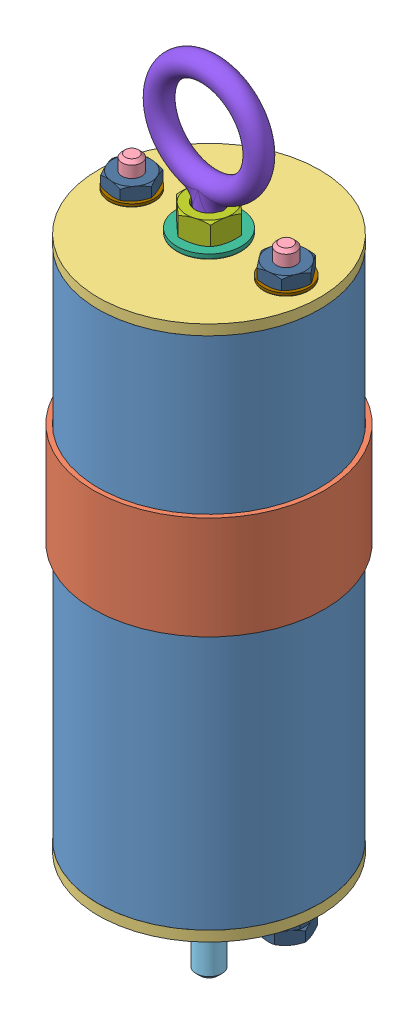
SolidWorks assembly Ebay Assembly, configuration Default. Lengths in mm.
Overall size (56.95 195.52 56.95).
37 component instances, 17 part files, 75 mates.
Components (placement in the parent):
- Coupler-1: Coupler [Default] at origin size (54.61 127 54.61)
- Body Tube-1: Body Tube [Switch Band] at (0 63.5 0) size (56.95 25.4 56.95)
- Bulkhead-1: Bulkhead [Default] at (0 -2.54 0) size (54.61 5.08 54.61)
- Bulkhead-2: Bulkhead [Default] at (0 129.54 0) x (-1 0 0) z (0 0 1) size (54.61 5.08 54.61)
- num10 threaded rod-1: num10 threaded rod [94435A511] at (19.05 63.5 0) x (0 -1 0) z (-0.767639 0 0.640883) size (147.32 4.83 4.83)
- num10 threaded rod-3: num10 threaded rod [94435A511] at (-19.05 63.5 0) x (0 -1 0) z (-0.633107 0 0.774065) size (147.32 4.83 4.83)
- 1-4 20 threaded rod-1: 1-4 20 threaded rod [94435A313] at (0 -8.89 0) x (0 1 0) z (-0.295098 0 0.955467) size (38.1 6.35 6.35)
- 1-4 washer-1: 1-4 washer [90107A029] at (0 -3.175 0) x (1 0 0) z (0 1 0) size (15.88 15.88 1.27)
- 1-4 washer-2: 1-4 washer [90107A029] at (0 3.175 0) x (-0.982082 0 -0.188455) z (0 -1 0) size (15.88 15.88 1.27)
- 1-4 20 nut-1: 1-4 20 nut [90670A029] at (0 6.5881 0) x (1 0 0) z (0 1 0) size (11.11 12.83 5.56)
- 1-4 20 nut-2: 1-4 20 nut [90670A029] at (0 -6.5881 0) x (-0.982082 0 -0.188455) z (0 -1 0) size (11.11 12.83 5.56)
- 1-4 washer-4: 1-4 washer [90107A029] at (0 123.825 0) x (0.982082 0 -0.188455) z (0 1 0) size (15.88 15.88 1.27)
- 1-4 washer-6: 1-4 washer [90107A029] at (0 130.175 0) x (-0.918365 0 -0.395734) z (0 -1 0) size (15.88 15.88 1.27)
- 1-4 20 nut-4: 1-4 20 nut [90670A029] at (0 120.4119 0) x (-1 0 0) z (0 -1 0) size (11.11 12.83 5.56)
- 1-4 20 nut-6: 1-4 20 nut [90670A029] at (0 133.5881 0) x (0.976488 0 0.215573) z (0 1 0) size (11.11 12.83 5.56)
- eyebolt-1: eyebolt [33045T71] at (0 152.499 0) size (30.16 50.16 7.13)
- num10 washer-1: num10 washer [90107A011] at (-19.05 129.9337 0) x (1 0 0) z (0 -1 0) size (11.13 11.13 0.79)
- num10 washer-2: num10 washer [90107A011] at (19.05 129.9337 0) x (0.982082 0 -0.188455) z (0 -1 0) size (11.13 11.13 0.79)
- num10 washer-4: num10 washer [90107A011] at (-19.05 -2.9337 0) x (-0.918365 0 -0.395734) z (0 1 0) size (11.13 11.13 0.79)
- num10 washer-6: num10 washer [90107A011] at (19.05 -2.9337 0) x (-0.8 0 -0.6) z (0 1 0) size (11.13 11.13 0.79)
- num10 nut-1: num10 nut [93181A011] at (-19.05 -4.9149 0) size (9.53 3.17 11)
- num10 nut-2: num10 nut [93181A011] at (19.05 -4.9149 0) x (0.982082 0 -0.188455) z (0.188455 0 0.982082) size (9.53 3.17 11)
- num10 nut-4: num10 nut [93181A011] at (19.05 131.9149 0) x (-0.918365 0 -0.395734) z (-0.395734 0 0.918365) size (9.53 3.17 11)
- num10 nut-6: num10 nut [93181A011] at (-19.05 131.9149 0) x (-0.8 0 -0.6) z (-0.6 0 0.8) size (9.53 3.17 11)
- num10 nut-8: num10 nut [93181A011] at (-19.05 -8.0899 0) x (0.982082 0 -0.188455) z (0.188455 0 0.982082) size (9.53 3.17 11)
- num10 nut-10: num10 nut [93181A011] at (19.05 -8.0899 0) x (0.918365 0 -0.395734) z (0.395734 0 0.918365) size (9.53 3.17 11)
- Ebay Sled-1: Ebay Sled [Default] at origin size (45.72 104.14 22.77)
- Raven 4 v9.step-1: Raven 4 v9.step [Default] at (10.033 113.03 9.3218) x (0 -1 0) z (0 0 -1) size (44.96 20.26 13.9)
- GPS Tracker v15.step-4: GPS Tracker v15.step [Default] at (-6.35 51.562 -9.652) x (0 -1 0) z (0 0 -1) size (103.47 20.32 17.72)
- easymini-1: easymini [Default] at (0 51.47 8.89) x (1 0 0) z (0 -1 0) size (38.1 12.95 20.32)
- 400mAh batt-1: 400mAh batt [Bottom] at (-3.7735 23.83 7.254) x (-1 0 0) z (0 0 -1) size (35.37 24.97 4.58)
- 400mAh batt-2: 400mAh batt [Bottom] at (-3.7735 23.83 11.754) x (-1 0 0) z (0 0 -1) size (35.37 24.97 4.58)
- 400mAh batt-3: 400mAh batt [Bottom] at (0 32.2622 0.874) x (0 1 0) z (0 0 1) size (35.37 24.97 4.58)
- Screw switch-1: Screw switch [Standard] at (-18.8981 72.4535 -9.8604) x (0 1 0) z (0.5 0 -0.866025) size (31.75 1.52 10.16)
- ss screw-1: ss screw [91772A142] at (-19.25 76.2 -10.0636) x (-0.09665 -0.98114 0.167404) z (-0.866025 0 -0.5) size (6.86 6.86 5.58)
- Screw switch-2: Screw switch [Standard] at (18.8981 72.4535 -9.8604) x (0 1 0) z (0.5 0 0.866025) size (31.75 1.52 10.16)
- ss screw-2: ss screw [91772A142] at (19.25 76.2 -10.0636) x (-0.09665 0.98114 -0.167404) z (0.866025 0 -0.5) size (6.86 6.86 5.58)
Mates (geometry in assembly coordinates):
- Concentric1: concentric aligned: cylinder of Coupler-1 through (0 127 0) axis (0 -1 0) radius 25.4; cylinder of Bulkhead-1 through (0 2.54 0) axis (0 -1 0) radius 25.4
- Coincident1: coincident anti-aligned: plane of Coupler-1 through (0 0 0) normal (0 -1 0); plane of Bulkhead-1 through (0 0 0) normal (0 1 0)
- Concentric2: concentric anti-aligned: cylinder of Coupler-1 through (0 127 0) axis (0 -1 0) radius 25.4; cylinder of Bulkhead-2 through (0 124.46 0) axis (0 1 0) radius 25.4
- Coincident2: coincident anti-aligned: plane of Coupler-1 through (0 127 0) normal (0 1 0); plane of Bulkhead-2 through (0 127 0) normal (0 -1 0)
- Concentric3: concentric aligned: cylinder of Coupler-1 through (0 127 0) axis (0 -1 0) radius 27.305; cylinder of Body Tube-1 through (0 88.9 0) axis (0 -1 0) radius 27.3304
- Distance1: distance = 63.5 mm aligned: plane of Coupler-1 through (0 0 0) normal (0 -1 0); plane of Body Tube-1 through (0 63.5 0) normal (0 -1 0)
- Concentric4: concentric anti-aligned: cylinder of Bulkhead-1 through (19.05 2.541 0) axis (0 -1 0) radius 2.413; cylinder of Bulkhead-2 through (19.05 124.459 0) axis (0 1 0) radius 2.413
- Concentric5: concentric anti-aligned: cylinder of Bulkhead-2 through (19.05 124.459 0) axis (0 1 0) radius 2.413; cylinder of num10 threaded rod-1 through (19.05 137.16 0) axis (0 -1 0) radius 2.413
- Width1: width aligned: plane of num10 threaded rod-1 through (19.05 137.16 0) normal (0 1 0); plane of num10 threaded rod-1 through (19.05 -10.16 0) normal (0 -1 0); plane of Bulkhead-2 through (0 129.54 0) normal (0 1 0); plane of Bulkhead-1 through (0 -2.54 0) normal (0 -1 0)
- Concentric6: concentric anti-aligned: cylinder of Bulkhead-2 through (-19.05 124.459 0) axis (0 1 0) radius 2.413; cylinder of num10 threaded rod-3 through (-19.05 137.16 0) axis (0 -1 0) radius 2.413
- Width2: width aligned: plane of num10 threaded rod-3 through (-19.05 137.16 0) normal (0 1 0); plane of num10 threaded rod-3 through (-19.05 -10.16 0) normal (0 -1 0); plane of Bulkhead-1 through (0 -2.54 0) normal (0 -1 0); plane of Bulkhead-2 through (0 129.54 0) normal (0 1 0)
- Concentric7: concentric anti-aligned: cylinder of num10 threaded rod-3 through (-19.05 137.16 0) axis (0 -1 0) radius 2.413; cylinder of num10 washer-1 through (-19.05 129.54 0) axis (0 1 0) radius 2.5781
- Coincident3: coincident anti-aligned: plane of Bulkhead-2 through (0 129.54 0) normal (0 1 0); plane of num10 washer-1 through (-19.05 129.54 0) normal (0 -1 0)
- Concentric8: concentric anti-aligned: cylinder of num10 threaded rod-1 through (19.05 137.16 0) axis (0 -1 0) radius 2.413; cylinder of num10 washer-2 through (19.05 129.54 0) axis (0 1 0) radius 2.5781
- Coincident4: coincident anti-aligned: plane of Bulkhead-2 through (0 129.54 0) normal (0 1 0); plane of num10 washer-2 through (19.05 129.54 0) normal (0 -1 0)
- Concentric9: concentric aligned: cylinder of num10 threaded rod-3 through (-19.05 137.16 0) axis (0 -1 0) radius 2.413; cylinder of num10 washer-4 through (-19.05 -2.54 0) axis (0 -1 0) radius 2.5781
- Coincident5: coincident anti-aligned: plane of Bulkhead-1 through (0 -2.54 0) normal (0 -1 0); plane of num10 washer-4 through (-19.05 -2.54 0) normal (0 1 0)
- Concentric10: concentric aligned: cylinder of num10 threaded rod-1 through (19.05 137.16 0) axis (0 -1 0) radius 2.413; cylinder of num10 washer-6 through (19.05 -2.54 0) axis (0 -1 0) radius 2.5781
- Coincident6: coincident anti-aligned: plane of Bulkhead-1 through (0 -2.54 0) normal (0 -1 0); plane of num10 washer-6 through (19.05 -2.54 0) normal (0 1 0)
- Concentric11: concentric aligned: cylinder of num10 threaded rod-3 through (-19.05 137.16 0) axis (0 -1 0) radius 2.413; cylinder of num10 nut-1 through (-19.05 -3.3274 0) axis (0 -1 0) radius 2.413
- Coincident7: coincident anti-aligned: plane of num10 washer-4 through (-19.05 -3.3274 0) normal (0 -1 0); plane of num10 nut-1 through (-23.8125 -3.3274 -2.7496) normal (0 1 0)
- Concentric12: concentric aligned: cylinder of num10 threaded rod-1 through (19.05 137.16 0) axis (0 -1 0) radius 2.413; cylinder of num10 nut-2 through (19.05 -3.3274 0) axis (0 -1 0) radius 2.413
- Coincident8: coincident anti-aligned: plane of num10 washer-6 through (19.05 -3.3274 0) normal (0 -1 0); plane of num10 nut-2 through (13.8547 -3.3274 -1.8028) normal (0 1 0)
- Concentric13: concentric anti-aligned: cylinder of num10 threaded rod-1 through (19.05 137.16 0) axis (0 -1 0) radius 2.413; cylinder of num10 nut-4 through (19.05 130.3274 0) axis (0 1 0) radius 2.413
- Coincident9: coincident anti-aligned: plane of num10 washer-2 through (19.05 130.3274 0) normal (0 1 0); plane of num10 nut-4 through (24.5118 130.3274 -0.6405) normal (0 -1 0)
- Concentric14: concentric anti-aligned: cylinder of num10 threaded rod-3 through (-19.05 137.16 0) axis (0 -1 0) radius 2.413; cylinder of num10 nut-6 through (-19.05 130.3274 0) axis (0 1 0) radius 2.413
- Coincident10: coincident anti-aligned: plane of num10 washer-1 through (-19.05 130.3274 0) normal (0 1 0); plane of num10 nut-6 through (-13.5902 130.3274 0.6578) normal (0 -1 0)
- Concentric15: concentric aligned: cylinder of num10 threaded rod-3 through (-19.05 137.16 0) axis (0 -1 0) radius 2.413; cylinder of num10 nut-8 through (-19.05 -6.5024 0) axis (0 -1 0) radius 2.413
- Coincident11: coincident anti-aligned: plane of num10 nut-1 through (-23.8125 -6.5024 -2.7496) normal (0 -1 0); plane of num10 nut-8 through (-24.2453 -6.5024 -1.8028) normal (0 1 0)
- Concentric16: concentric aligned: cylinder of num10 threaded rod-1 through (19.05 137.16 0) axis (0 -1 0) radius 2.413; cylinder of num10 nut-10 through (19.05 -6.5024 0) axis (0 -1 0) radius 2.413
- Coincident12: coincident anti-aligned: plane of num10 nut-2 through (13.8547 -6.5024 -1.8028) normal (0 -1 0); plane of num10 nut-10 through (13.5882 -6.5024 -0.6405) normal (0 1 0)
- Distance2: distance = 7.62 mm aligned: plane of 1-4 20 threaded rod-1 through (0 10.16 0) normal (0 1 0); plane of Bulkhead-1 through (0 2.54 0) normal (0 1 0)
- Concentric18: concentric anti-aligned: cylinder of Bulkhead-1 through (0 2.541 0) axis (0 -1 0) radius 3.3346; cylinder of 1-4 20 threaded rod-1 through (0 -27.94 0) axis (0 1 0) radius 3.175
- Concentric19: concentric anti-aligned: cylinder of 1-4 20 threaded rod-1 through (0 -27.94 0) axis (0 1 0) radius 3.175; cylinder of 1-4 washer-1 through (0 -2.54 0) axis (0 -1 0) radius 3.5687
- Coincident13: coincident anti-aligned: plane of Bulkhead-1 through (0 -2.54 0) normal (0 -1 0); plane of 1-4 washer-1 through (0 -2.54 0) normal (0 1 0)
- Concentric20: concentric aligned: cylinder of 1-4 20 threaded rod-1 through (0 -27.94 0) axis (0 1 0) radius 3.175; cylinder of 1-4 washer-2 through (0 2.54 0) axis (0 1 0) radius 3.5687
- Coincident14: coincident anti-aligned: plane of Bulkhead-1 through (0 2.54 0) normal (0 1 0); plane of 1-4 washer-2 through (0 2.54 0) normal (0 -1 0)
- Concentric21: concentric anti-aligned: cylinder of 1-4 20 threaded rod-1 through (0 -27.94 0) axis (0 1 0) radius 3.175; cylinder of 1-4 20 nut-1 through (0 9.3662 0) axis (0 -1 0) radius 3.175
- Coincident15: coincident anti-aligned: plane of 1-4 washer-2 through (0 3.81 0) normal (0 1 0); plane of 1-4 20 nut-1 through (-5.5563 3.81 -3.2079) normal (0 -1 0)
- Concentric22: concentric aligned: cylinder of 1-4 20 threaded rod-1 through (0 -27.94 0) axis (0 1 0) radius 3.175; cylinder of 1-4 20 nut-2 through (0 -9.3662 0) axis (0 1 0) radius 3.175
- Coincident16: coincident anti-aligned: plane of 1-4 washer-1 through (0 -3.81 0) normal (0 -1 0); plane of 1-4 20 nut-2 through (6.0612 -3.81 -2.1033) normal (0 1 0)
- Concentric23: concentric anti-aligned: cylinder of Bulkhead-2 through (0 124.459 0) axis (0 1 0) radius 3.3346; cylinder of 1-4 washer-4 through (0 124.46 0) axis (0 -1 0) radius 3.5687
- Coincident17: coincident anti-aligned: plane of Bulkhead-2 through (0 124.46 0) normal (0 -1 0); plane of 1-4 washer-4 through (0 124.46 0) normal (0 1 0)
- Concentric24: concentric aligned: line of Bulkhead-2 through (0 124.46 0) axis (0 1 0); cylinder of 1-4 washer-6 through (0 129.54 0) axis (0 1 0) radius 3.5687
- Coincident18: coincident anti-aligned: plane of Bulkhead-2 through (0 129.54 0) normal (0 1 0); plane of 1-4 washer-6 through (0 129.54 0) normal (0 -1 0)
- Concentric25: concentric aligned: cylinder of Bulkhead-2 through (0 124.459 0) axis (0 1 0) radius 3.3346; cylinder of 1-4 20 nut-4 through (0 117.6337 0) axis (0 1 0) radius 3.175
- Coincident19: coincident anti-aligned: plane of 1-4 washer-4 through (0 123.19 0) normal (0 -1 0); plane of 1-4 20 nut-4 through (5.5563 123.19 -3.2079) normal (0 1 0)
- Concentric26: concentric anti-aligned: cylinder of Bulkhead-2 through (0 124.459 0) axis (0 1 0) radius 3.3346; cylinder of 1-4 20 nut-6 through (0 136.3663 0) axis (0 -1 0) radius 3.175
- Coincident20: coincident anti-aligned: plane of 1-4 washer-6 through (0 130.81 0) normal (0 1 0); plane of 1-4 20 nut-6 through (-4.7341 130.81 -4.3303) normal (0 -1 0)
- Concentric27: concentric anti-aligned: cylinder of 1-4 20 nut-6 through (0 136.3663 0) axis (0 -1 0) radius 3.175; cylinder of eyebolt-1 through (0 107.2552 0) axis (0 1 0) radius 3.175
- Width3: width anti-aligned: plane of Ebay Sled-1 through (22.86 171.2953 -5.08) normal (1 0 0); plane of Ebay Sled-1 through (-22.86 171.2953 -5.08) normal (-1 0 0); plane of GPS Tracker v15.step-4 through (-10.16 12.7 -9.652) normal (-1 0 0); plane of GPS Tracker v15.step-4 through (10.16 52.832 -9.652) normal (1 0 0)
- Distance8: distance = 4.572 mm anti-aligned: plane of Part1^Ebay Assembly-1 through (-22.86 171.2953 -5.08) normal (0 0 -1); plane of GPS Tracker v15.step-4 through (0 33.782 -9.652) normal (0 0 1)
- Distance9: distance = 1.27 mm aligned: plane of Part1^Ebay Assembly-1 through (0 11.43 0) normal (0 -1 0); plane of GPS Tracker v15.step-4 through (10.16 12.7 -9.652) normal (0 -1 0)
- Coincident24: coincident anti-aligned: plane of Part1^Ebay Assembly-1 through (-22.86 171.2953 5.08) normal (0 0 1); plane of 400mAh batt-1 through (16.5614 36.23 5.08) normal (0 0 -1)
- Distance11: distance = 2.54 mm anti-aligned: plane of Part1^Ebay Assembly-1 through (-22.86 171.2953 5.08) normal (0 0 1); plane of Raven 4 v9.step-1 through (0 90.551 7.62) normal (0 0 -1)
- Distance12: distance = 3.81 mm anti-aligned: plane of easymini-1 through (0 51.47 8.89) normal (0 0 -1); plane of Part1^Ebay Assembly-1 through (-22.86 171.2953 5.08) normal (0 0 1)
- Parallel1: parallel aligned: plane of Part1^Ebay Assembly-1 through (0 11.43 0) normal (0 -1 0); plane of easymini-1 through (19.05 41.31 10.414) normal (0 -1 0)
- Parallel2: parallel aligned: plane of Part1^Ebay Assembly-1 through (22.86 171.2953 -5.08) normal (1 0 0); plane of Raven 4 v9.step-1 through (10.033 113.03 9.3218) normal (1 0 0)
- Coincident25: coincident anti-aligned: plane of 400mAh batt-1 through (16.5614 13.23 9.58) normal (0 0 1); plane of 400mAh batt-2 through (16.5614 36.23 9.58) normal (0 0 -1)
- Coincident26: coincident aligned: plane of 400mAh batt-1 through (16.5614 36.23 9.136) normal (0 1 0); plane of 400mAh batt-2 through (16.5614 36.23 13.636) normal (0 1 0)
- Coincident27: coincident aligned: plane of 400mAh batt-1 through (16.8614 23.83 7.108) normal (1 0 0); plane of 400mAh batt-2 through (16.8614 23.83 11.608) normal (1 0 0)
- Coincident28: coincident anti-aligned: plane of Part1^Ebay Assembly-1 through (101.8356 102.87 3.048) normal (0 0 -1); plane of 400mAh batt-3 through (-12.4 11.9272 3.048) normal (0 0 1)
- Width4: width anti-aligned: plane of Ebay Sled-1 through (13.462 142.9691 2.54) normal (-1 0 0); plane of Ebay Sled-1 through (-13.462 142.9691 2.54) normal (1 0 0); plane of 400mAh batt-3 through (12.4 11.9272 3.048) normal (1 0 0); plane of 400mAh batt-3 through (-12.4 11.9272 -1.008) normal (-1 0 0)
- Coincident31: coincident aligned: plane of Screw switch-1 through (-18.8981 76.2 -9.8604) normal (0 1 0)
- Angle1: planar angle = 1.047198 rad anti-aligned: plane of Part1^Ebay Assembly-1 through (-22.86 171.2953 -5.08) normal (0 0 -1); plane of Screw switch-1 through (-18.2382 72.4535 -9.4794) normal (0.866025 0 0.5)
- Coincident34: coincident: plane of Part1^Ebay Assembly-1 through (-22.86 171.2953 -5.08) normal (0 0 -1); line of Screw switch-1 through (-20.7782 88.3285 -5.08) axis (0 -1 0)
- Distance13: distance = 0.762 mm: line of Screw switch-1 through (-22.098 88.3285 -5.842) axis (0 -1 0); plane of Part1^Ebay Assembly-1 through (-22.86 171.2953 -5.08) normal (-1 0 0)
- Concentric28: concentric anti-aligned: cylinder of Screw switch-1 through (-18.8981 76.2 -9.8604) axis (0.866025 0 0.5) radius 1.8669; cylinder of ss screw-1 through (-21.6917 76.2 -11.4733) axis (-0.866025 0 -0.5) radius 1.7526
- Coincident35: coincident anti-aligned: plane of Screw switch-1 through (-19.558 72.4535 -10.2414) normal (-0.866025 0 -0.5); plane of ss screw-1 through (-20.4178 76.5388 -8.7522) normal (0.866025 0 0.5)
- Coincident36: coincident aligned: plane of Ebay Sled-1 through (0 11.43 0) normal (0 -1 0); plane of 400mAh batt-1 through (16.5614 11.43 5.08) normal (0 -1 0)
- Width5: width anti-aligned: plane of Ebay Sled-1 through (22.86 171.2953 -5.08) normal (1 0 0); plane of 400mAh batt-1 through (-22.86 171.2953 -5.08) normal (-1 0 0); plane of Ebay Sled-1 through (-16.8614 12.8709 5.08) normal (-1 0 0); plane of 400mAh batt-1 through (16.8614 23.83 7.108) normal (1 0 0)
- Width6: width anti-aligned: plane of Ebay Sled-1 through (22.86 171.2953 -5.08) normal (1 0 0); plane of easymini-1 through (-22.86 171.2953 -5.08) normal (-1 0 0); plane of Ebay Sled-1 through (-19.05 41.31 10.414) normal (-1 0 0); plane of easymini-1 through (19.05 41.31 10.414) normal (1 0 0)
- Distance14: distance = 5.08 mm anti-aligned: plane of easymini-1 through (19.05 41.31 10.414) normal (0 -1 0); plane of 400mAh batt-2 through (16.5614 36.23 13.636) normal (0 1 0)
- Width7: width anti-aligned: plane of Raven 4 v9.step-1 through (-10.033 68.072 9.3218) normal (-1 0 0); plane of Ebay Sled-1 through (10.033 113.03 9.3218) normal (1 0 0); plane of Raven 4 v9.step-1 through (22.86 171.2953 -5.08) normal (1 0 0); plane of Ebay Sled-1 through (-22.86 171.2953 -5.08) normal (-1 0 0)
- Distance15: distance = 2.54 mm aligned: plane of Ebay Sled-1 through (0 115.57 0) normal (0 1 0); plane of Raven 4 v9.step-1 through (-10.033 113.03 9.3218) normal (0 1 0)
